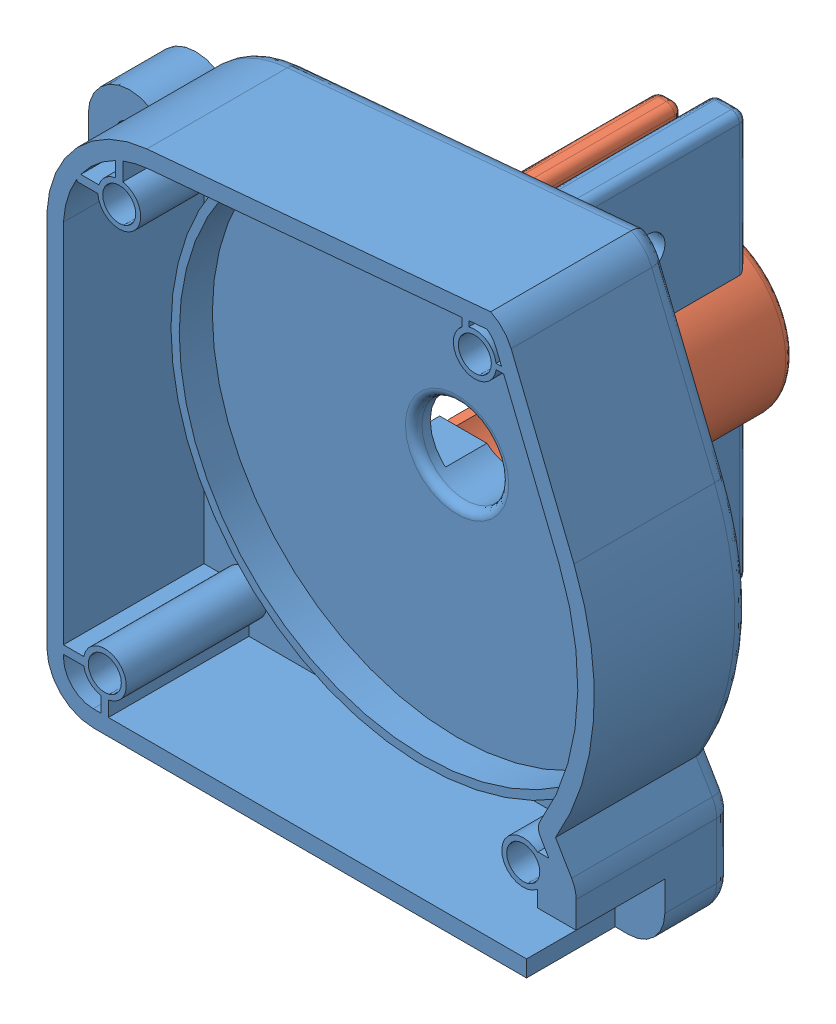
SolidWorks assembly casing assem, configuration Default. Lengths in mm.
Overall size (96.78 85.99 60.82).
2 component instances, 2 part files, 3 mates.
Components (placement in the parent):
- casing-1: casing [Default] at (15.5037 15.1158 -17.5958) size (96.78 85.99 58.43)
- pot-cap-1: pot-cap [Default] at (15.5037 15.1158 -56.7118) x (-1 0 0) z (0 0 1) size (25.27 63.08 30.46)
Mates (geometry in assembly coordinates):
- Concentric2: concentric anti-aligned: cylinder of casing-1 through (15.5037 15.1158 -26.4858) axis (0 0 1) radius 12.6373; cylinder of pot-cap-1 through (15.5037 15.1158 -54.4258) axis (0 0 -1) radius 12.6365
- Coincident2: coincident aligned: plane of casing-1 through (15.5037 15.1158 -26.4858) normal (0 0 -1); circle of pot-cap-1
- Parallel2: parallel anti-aligned: plane of pot-cap-1 through (17.4087 27.6079 -26.4858) normal (1 0 0); plane of casing-1 through (18.2215 15.1158 -54.4258) normal (-1 0 0)
